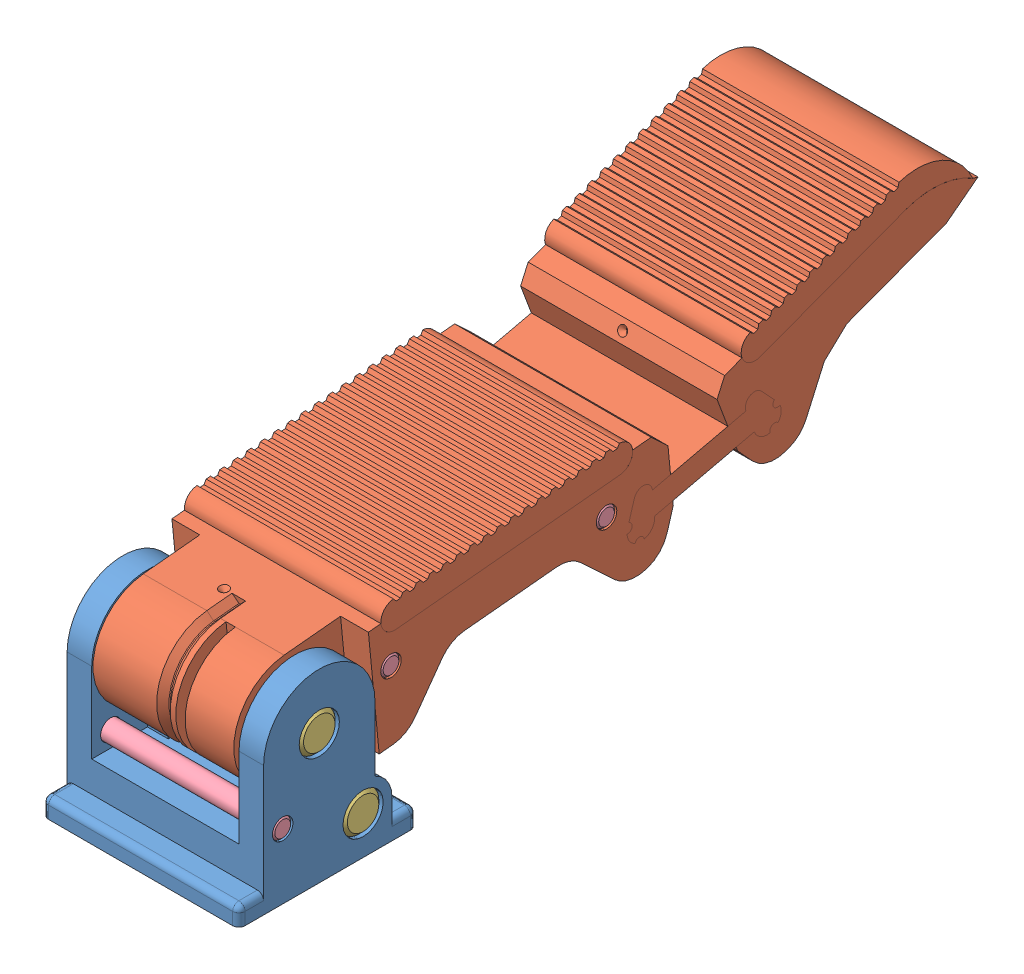
SolidWorks assembly block_finger_pf_t42, configuration Default. Lengths in mm.
Overall size (32.08 52.28 121.98).
9 component instances, 6 part files, 16 mates.
Components (placement in the parent):
- c1_t42-1: c1_t42 [Default] at origin size (31.75 29.94 28.75)
- t42_pf-1: t42_pf [Default] at (-0.325 20.9353 -30) x (1 0 0) z (0 -0.096781 0.995306) size (31.75 29.93 117.62)
- 98381A544 D1-4 L5-4-1: 98381A544 D1-4 L5-4 [98381A544] at (0 20.9353 -30) size (31.75 6.35 6.35)
- 98381A544 D1-4 L5-4-2: 98381A544 D1-4 L5-4 [98381A544] at (0 6.175 -37.075) size (31.75 6.35 6.35)
- 98381A477 D1-8 L5-4-1: 98381A477 D1-8 L5-4 [98381A477] at (0 10.5228 -24.0875) size (31.75 3.17 3.17)
- 98381A477 D1-8 L5-4-2: 98381A477 D1-8 L5-4 [98381A477] at (-0.325 24.2659 -41.9086) size (31.75 3.17 3.17)
- 98381A477 D1-8 L5-4-3: 98381A477 D1-8 L5-4 [98381A477] at (-0.325 27.6532 -76.7438) size (31.75 3.17 3.17)
- 93365A120 4-40 insert-1: 93365A120 4-40 insert [93365A120] at (-0.325 33.5905 -113.7566) x (1 0 0) z (0 0.685717 -0.727868) size (4.37 3.82 4.37)
- 91253A106 4-40 L1-4 countersunk-1: 91253A106 4-40 L1-4 countersunk [91253A106] at (-0.325 32.3511 -114.9242) x (1 0 0) z (0 -0.727868 -0.685717) size (6.48 6.48 6.63)
Mates (geometry in assembly coordinates):
- Concentric1: concentric: cylinder of c1_t42-1 through (-15.875 20.9353 -30) axis (1 0 0) radius 3.25; cylinder of 98381A544 D1-4 L5-4-1 through (-15.875 20.9353 -30) axis (1 0 0) radius 3.175
- Coincident1: coincident: plane of c1_t42-1 through (15.875 20.9353 -30) normal (1 0 0); plane of 98381A544 D1-4 L5-4-1 through (15.875 20.9353 -30) normal (1 0 0)
- Concentric2: concentric: cylinder of c1_t42-1 through (-15.875 10.5228 -24.0875) axis (1 0 0) radius 1.6625; cylinder of 98381A477 D1-8 L5-4-1 through (-15.875 10.5228 -24.0875) axis (1 0 0) radius 1.5875
- Coincident2: coincident: plane of c1_t42-1 through (15.875 20.9353 -30) normal (1 0 0); plane of 98381A477 D1-8 L5-4-1 through (15.875 10.5228 -24.0875) normal (1 0 0)
- Concentric3: concentric: cylinder of c1_t42-1 through (-15.875 6.175 -37.075) axis (1 0 0) radius 3.25; cylinder of 98381A544 D1-4 L5-4-2 through (-15.875 6.175 -37.075) axis (1 0 0) radius 3.175
- Coincident3: coincident: plane of c1_t42-1 through (15.875 20.9353 -30) normal (1 0 0); plane of 98381A544 D1-4 L5-4-2 through (15.875 6.175 -37.075) normal (1 0 0)
- Concentric4: concentric: cylinder of t42_pf-1 through (-16.2 24.2659 -41.9086) axis (1 0 0) radius 1.6625; cylinder of 98381A477 D1-8 L5-4-2 through (-16.2 24.2659 -41.9086) axis (1 0 0) radius 1.5875
- Coincident4: coincident: plane of t42_pf-1 through (15.55 20.9353 -30) normal (1 0 0); plane of 98381A477 D1-8 L5-4-2 through (15.55 24.2659 -41.9086) normal (1 0 0)
- Concentric5: concentric: cylinder of t42_pf-1 through (-16.2 27.6532 -76.7438) axis (1 0 0) radius 1.6625; cylinder of 98381A477 D1-8 L5-4-3 through (-16.2 27.6532 -76.7438) axis (1 0 0) radius 1.5875
- Coincident5: coincident: plane of t42_pf-1 through (15.55 20.9353 -30) normal (1 0 0); plane of 98381A477 D1-8 L5-4-3 through (15.55 27.6532 -76.7438) normal (1 0 0)
- Concentric6: concentric: cylinder of t42_pf-1 through (-16.2 20.9353 -30) axis (1 0 0) radius 3.35; cylinder of 98381A544 D1-4 L5-4-1 through (-15.875 20.9353 -30) axis (1 0 0) radius 3.175
- Distance1: distance = 0.2 mm: plane of c1_t42-1 through (-11.9 20.9353 -30) normal (1 0 0); plane of t42_pf-1 through (-11.7 12.8655 -40.003) normal (-1 0 0)
- Concentric7: concentric: cylinder of t42_pf-1 through (-0.325 36.8659 -110.6709) axis (0 -0.727868 -0.685717) radius 1.85; circle of 93365A120 4-40 insert-1
- Coincident7: coincident: plane of t42_pf-1 through (-21.2 31.8762 -111.9369) normal (0 -0.727868 -0.685717); plane of 93365A120 4-40 insert-1 through (-0.325 33.5905 -113.7566) normal (0 -0.727868 -0.685717)
- Concentric8: concentric: circle of t42_pf-1; circle of 91253A106 4-40 L1-4 countersunk-1
- Coincident8: coincident: circle of t42_pf-1; cone of 91253A106 4-40 L1-4 countersunk-1 through (-0.325 33.8856 -113.4785) axis (0 0.727868 0.685717)
